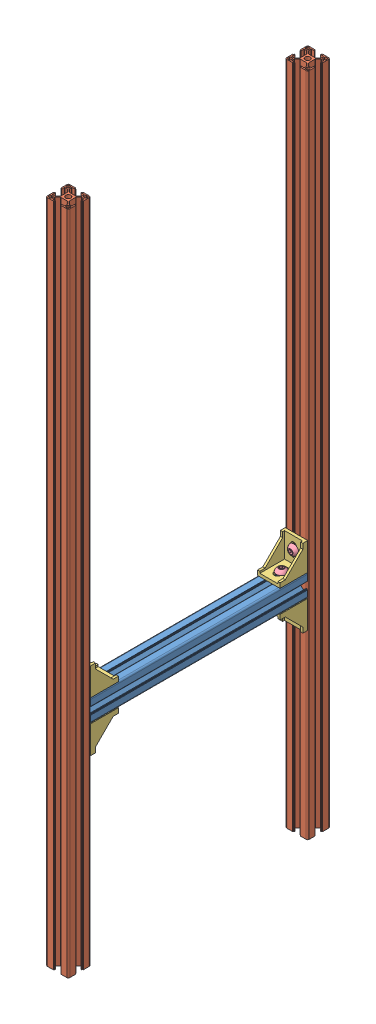
SolidWorks assembly H型拉杆架, configuration 默认. Lengths in mm.
Overall size (30 890 350).
27 component instances, 5 part files, 16 mates.
Components (placement in the parent):
- 3030_290mm-1: 3030_290mm [默认] at (-10.2692 -0.2729 145) size (30 30 290)
- 3030_890mm-1: 3030_890mm [默认] at (-10.2692 594.7271 130) x (0 0 -1) z (0 -1 0) size (30 30 890)
- 3030_890mm-2: 3030_890mm [默认] at (-10.2692 594.7271 450) x (0 0 -1) z (0 -1 0) size (30 30 890)
- 角码+螺栓-1: 角码+螺栓 [默认] at (26.7308 31.2131 423.3834) x (0 0 1) z (-1 0 0) size (47 47 30)
  - 3030角码-1: 3030角码 [默认] at (-4.7227 -3.6958 22) size (37 37 30)
  - hexagon socket button head screws gb-1: hexagon socket button head screws gb [GB_SOCKET_TYPE7 M8X14-S] at (3.2166 3.743 36.75) x (1 0 0) z (0 0.018323 0.999832) size (18.4 14 14)
  - square nuts--product grade c gb-1: square nuts--product grade c gb [GB_SPECIAL_TYPE12 M8-C] at (19.9166 3.743 36.75) x (0 0.707107 -0.707107) z (1 0 0) size (18.38 18.38 6.5)
  - hexagon socket button head screws gb-2: hexagon socket button head screws gb [GB_SOCKET_TYPE7 M8X14-S] at (-9.1015 -8.086 36.75) x (0 -1 0) z (-0.830458 0 -0.557081) size (18.4 14 14)
  - square nuts--product grade c gb-2: square nuts--product grade c gb [GB_SPECIAL_TYPE12 M8-C] at (-9.1015 -24.786 36.75) x (0.707107 0 -0.707107) z (0 -1 0) size (18.38 18.38 6.5)
- 角码+螺栓-2: 角码+螺栓 [默认] at (-47.2692 -26.8895 161.486) x (0 1 0) z (1 0 0) size (47 47 30)
  - 3030角码-1: 3030角码 [默认] at (-4.7227 -3.6958 22) size (37 37 30)
  - hexagon socket button head screws gb-1: hexagon socket button head screws gb [GB_SOCKET_TYPE7 M8X14-S] at (3.2166 3.743 36.75) x (1 0 0) z (0 0.018323 0.999832) size (18.4 14 14)
  - square nuts--product grade c gb-1: square nuts--product grade c gb [GB_SPECIAL_TYPE12 M8-C] at (19.9166 3.743 36.75) x (0 0.707107 -0.707107) z (1 0 0) size (18.38 18.38 6.5)
  - hexagon socket button head screws gb-2: hexagon socket button head screws gb [GB_SOCKET_TYPE7 M8X14-S] at (-9.1015 -8.086 36.75) x (0 -1 0) z (-0.830458 0 -0.557081) size (18.4 14 14)
  - square nuts--product grade c gb-2: square nuts--product grade c gb [GB_SPECIAL_TYPE12 M8-C] at (-9.1015 -24.786 36.75) x (0.707107 0 -0.707107) z (0 -1 0) size (18.38 18.38 6.5)
- 角码+螺栓-3: 角码+螺栓 [默认] at (26.7308 26.3438 161.486) x (0 -1 0) z (-1 0 0) size (47 47 30)
  - 3030角码-1: 3030角码 [默认] at (-4.7227 -3.6958 22) size (37 37 30)
  - hexagon socket button head screws gb-1: hexagon socket button head screws gb [GB_SOCKET_TYPE7 M8X14-S] at (3.2166 3.743 36.75) x (1 0 0) z (0 0.018323 0.999832) size (18.4 14 14)
  - square nuts--product grade c gb-1: square nuts--product grade c gb [GB_SPECIAL_TYPE12 M8-C] at (19.9166 3.743 36.75) x (0 0.707107 -0.707107) z (1 0 0) size (18.38 18.38 6.5)
  - hexagon socket button head screws gb-2: hexagon socket button head screws gb [GB_SOCKET_TYPE7 M8X14-S] at (-9.1015 -8.086 36.75) x (0 -1 0) z (-0.830458 0 -0.557081) size (18.4 14 14)
  - square nuts--product grade c gb-2: square nuts--product grade c gb [GB_SPECIAL_TYPE12 M8-C] at (-9.1015 -24.786 36.75) x (0.707107 0 -0.707107) z (0 -1 0) size (18.38 18.38 6.5)
- 角码+螺栓-4: 角码+螺栓 [默认] at (26.7308 -26.8895 418.514) x (0 1 0) z (-1 0 0) size (47 47 30)
  - 3030角码-1: 3030角码 [默认] at (-4.7227 -3.6958 22) size (37 37 30)
  - hexagon socket button head screws gb-1: hexagon socket button head screws gb [GB_SOCKET_TYPE7 M8X14-S] at (3.2166 3.743 36.75) x (1 0 0) z (0 0.018323 0.999832) size (18.4 14 14)
  - square nuts--product grade c gb-1: square nuts--product grade c gb [GB_SPECIAL_TYPE12 M8-C] at (19.9166 3.743 36.75) x (0 0.707107 -0.707107) z (1 0 0) size (18.38 18.38 6.5)
  - hexagon socket button head screws gb-2: hexagon socket button head screws gb [GB_SOCKET_TYPE7 M8X14-S] at (-9.1015 -8.086 36.75) x (0 -1 0) z (-0.830458 0 -0.557081) size (18.4 14 14)
  - square nuts--product grade c gb-2: square nuts--product grade c gb [GB_SPECIAL_TYPE12 M8-C] at (-9.1015 -24.786 36.75) x (0.707107 0 -0.707107) z (0 -1 0) size (18.38 18.38 6.5)
Mates (geometry in assembly coordinates):
- 同心1: concentric: cylinder of 3030_290mm-1 through (-10.2692 -0.2729 145) axis (0 0 1) radius 3.4; cylinder of 3030_890mm-1 through (-10.2692 -0.2729 140) axis (0 0 -1) radius 4.05
- 同心2: concentric: cylinder of 3030_290mm-1 through (-10.2692 -0.2729 145) axis (0 0 1) radius 3.4; cylinder of 3030_890mm-2 through (-10.2692 -0.2729 460) axis (0 0 -1) radius 4.05
- 重合1: coincident: plane of 3030_290mm-1 through (-10.2692 -0.2729 145) normal (0 0 -1); plane of 3030_890mm-1 through (-5.1692 -295.2729 145) normal (0 0 1)
- 重合2: coincident: plane of 3030_290mm-1 through (-10.2692 -0.2729 435) normal (0 0 1); plane of 3030_890mm-2 through (-5.1692 -295.2729 435) normal (0 0 -1)
- 重合3: coincident: plane of 3030_890mm-1 through (4.7308 -295.2729 135.1) normal (1 0 0); plane of 角码+螺栓-3/3030角码-1 through (4.7308 31.0664 157.7902) normal (1 0 0)
- 重合4: coincident: plane of 3030_890mm-1 through (-5.1692 -295.2729 145) normal (0 0 1); plane of 角码+螺栓-3/3030角码-1 through (-25.2692 51.7271 145) normal (0 0 -1)
- 重合7: coincident: plane of 3030_890mm-1 through (-15.3692 -295.2729 145) normal (0 0 1); plane of 角码+螺栓-2/3030角码-1 through (4.7308 -52.2729 145) normal (0 0 -1)
- 重合8: coincident: plane of 3030_890mm-1 through (4.7308 -295.2729 135.1) normal (1 0 0); plane of 角码+螺栓-2/3030角码-1 through (4.7308 -31.6121 157.7902) normal (1 0 0)
- 重合9: coincident: plane of 3030_890mm-2 through (4.7308 -295.2729 444.9) normal (1 0 0); plane of 角码+螺栓-4/3030角码-1 through (4.7308 -31.6121 422.2098) normal (1 0 0)
- 重合11: coincident: plane of 3030_890mm-2 through (-5.1692 -295.2729 435) normal (0 0 -1); plane of 角码+螺栓-4/3030角码-1 through (-25.2692 -52.2729 435) normal (0 0 1)
- 重合12: coincident: plane of 3030_890mm-2 through (-5.1692 -295.2729 435) normal (0 0 -1); plane of 角码+螺栓-1/3030角码-1 through (-25.2692 51.7271 435) normal (0 0 1)
- 重合14: coincident: plane of 3030_890mm-2 through (4.7308 -295.2729 444.9) normal (1 0 0); plane of 角码+螺栓-1/3030角码-1 through (4.7308 27.5173 418.6607) normal (1 0 0)
- 重合15: coincident: plane of 3030_290mm-1 through (-5.1692 14.7271 435) normal (0 1 0); plane of 角码+螺栓-1/3030角码-1 through (-25.2692 14.7271 398) normal (0 -1 0)
- 重合16: coincident: plane of 3030_290mm-1 through (-15.3692 -15.2729 435) normal (0 -1 0); plane of 角码+螺栓-4/3030角码-1 through (-25.2692 -15.2729 398) normal (0 1 0)
- 重合18: coincident: plane of 3030_290mm-1 through (-5.1692 -15.2729 435) normal (0 -1 0); plane of 角码+螺栓-2/3030角码-1 through (4.7308 -15.2729 182) normal (0 1 0)
- 重合19: coincident: plane of 3030_290mm-1 through (-15.3692 14.7271 435) normal (0 1 0); plane of 角码+螺栓-3/3030角码-1 through (-25.2692 14.7271 182) normal (0 -1 0)
